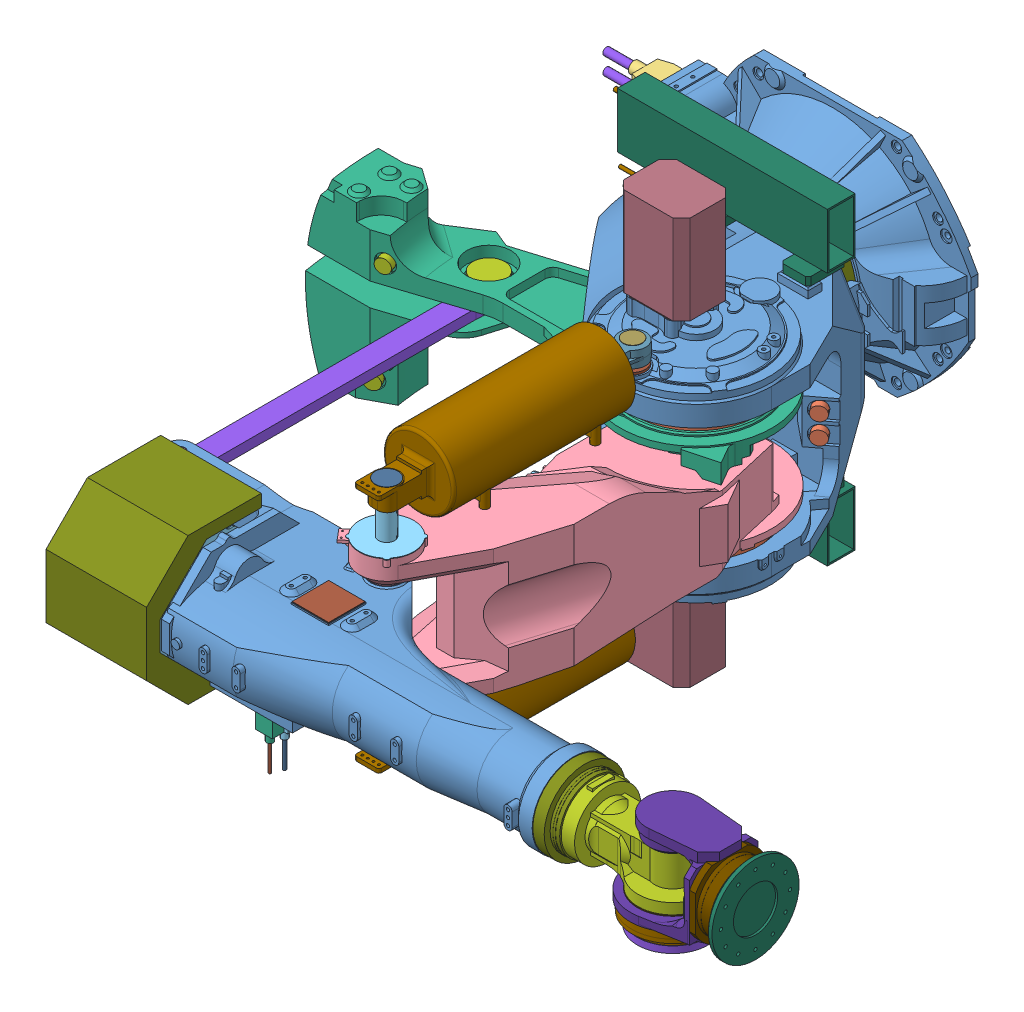
SolidWorks assembly 3D_M-900iB_700_v01, configuration По умолчанию. Lengths in mm.
Overall size (2849.18 1471 2580).
68 component instances, 53 part files, 0 mates.
Components (placement in the parent):
- S301_yellow_v1-1: S301_yellow_v1 [По умолчанию] at (0 0 940) size (1031 816 962)
- S301_black_v1-1: S301_black_v1 [По умолчанию] at (0 0 940) size (948 1369 773)
- S301_red_v1-1: S301_red_v1 [По умолчанию] at (0 0 940) size (615.67 1451.6 218.5)
- S302_yellow_v1-1: S302_yellow_v1 [По умолчанию] at (410 0 940) x (-1 0 0) z (0 0 1) size (586.92 532 1493.5)
- S302_black_v1-1: S302_black_v1 [По умолчанию] at (410 0 940) x (-1 0 0) z (0 0 1) size (238.62 719 787.58)
- S303_yellow_v1-1: S303_yellow_v1 [По умолчанию] at (410 178 940) size (1549.97 633 548)
- S303_black_v1-1: S303_black_v1 [По умолчанию] at (410 178 940) size (313.77 444 276.38)
- S304_yellow_v1-1: S304_yellow_v1 [По умолчанию] at (-340 51 2060) size (116 53 1230)
- S305_yellow_v1-1: S305_yellow_v1 [По умолчанию] at (410 394.5 1945.5) x (0 1 0) z (0 0 1) size (264 257 844.5)
- S305_yellow_v1-2: S305_yellow_v1 [По умолчанию] at (410 -394.5 1945.5) x (0 -1 0) z (0 0 1) size (264 257 844.5)
- S305_black_v1-1: S305_black_v1 [По умолчанию] at (410 435.7 2060) size (82 1.2 82)
- S305_black_v1-2: S305_black_v1 [По умолчанию] at (410 -434.5 2060) size (82 1.2 82)
- S301_black_v2-1: S301_black_v2 [По умолчанию] at (410 -345.5 1170) x (1 0 0) z (0 -1 0) size (93 93 20)
- S301_black_v2-2: S301_black_v2 [По умолчанию] at (410 345.5 1170) x (1 0 0) z (0 1 0) size (93 93 20)
- S306_black_v1-1: S306_black_v1 [По умолчанию] at (410 429.7 1170) x (1 0 0) z (0 -1 0) size (68 68 6.2)
- S306_black_v1-2: S306_black_v1 [По умолчанию] at (410 -429.7 1170) x (1 0 0) z (0 1 0) size (68 68 6.2)
- S309_black_v1-1: S309_black_v1 [По умолчанию] at (410 -135 2060) x (1 0 0) z (0 -1 0) size (109.6 109.6 10)
- S309_black_v1-2: S309_black_v1 [По умолчанию] at (410 135 2060) x (1 0 0) z (0 1 0) size (109.6 109.6 10)
- S306_yellow_v1-1: S306_yellow_v1 [По умолчанию] at (410 394.5 1170) x (1 0 0) z (0 -1 0) size (98 125 58)
- S306_yellow_v1-2: S306_yellow_v1 [По умолчанию] at (410 -394.5 1170) x (-1 0 0) z (0 1 0) size (98 125 58)
- S306_silver_v1-1: S306_silver_v1 [По умолчанию] at (410 -394.5 1922) x (1 0 0) z (0 1 0) size (40 600 40)
- S306_silver_v1-2: S306_silver_v1 [По умолчанию] at (410 394.5 1922) x (1 0 0) z (0 1 0) size (40 600 40)
- S401_black_v4-1: S401_black_v4 [По умолчанию] at (410 0 2060) size (1648.5 486.68 390.84)
- S511_yellow_v1-1: S511_yellow_v1 [По умолчанию] at (1695 0 2310) x (1 0 0) z (0 1 0) size (363 306 300.5)
- S401_red_v2-1: S401_red_v2 [По умолчанию] at (410 0 2060) size (41.3 434 304)
- S401_yellow_v1-1: S401_yellow_v1 [По умолчанию] at (410 0 2060) size (1734.5 454 556.62)
- S401_black_v1-1: S401_black_v1 [По умолчанию] at (-340 43 2060) x (1 0 0) z (0 1 0) size (50 50 8)
- S401_red_v1-1: S401_red_v1 [По умолчанию] at (-340 114.8 2060) x (1 0 0) z (0 -1 0) size (70 70 10.8)
- S401_black_v2-1: S401_black_v2 [По умолчанию] at (-340 143.7 2060) x (1 0 0) z (0 -1 0) size (40 40 28.9)
- S401_yellow_v2-1: S401_yellow_v2 [По умолчанию] at (40 0 2310) x (0 -1 0) z (0 0 1) size (500 20 388.5)
- S401_black_v3-1: S401_black_v3 [По умолчанию] at (-340 6 2060) x (1 0 0) z (0 1 0) size (116 116 37)
- S501_yellow_v2-1: S501_yellow_v2 [По умолчанию] at (1695 0 2310) x (1 0 0) z (0 -1 0) size (408 250 246)
- S501_yellow_v3-1: S501_yellow_v3 [По умолчанию] at (1695 -198 2310) x (1 0 0) z (0 1 0) size (255 255 24)
- S501_black_v2-1: S501_black_v2 [По умолчанию] at (1695 -80 2310) x (1 0 0) z (0 -1 0) size (295 295 114)
- S310_yellow_v1-1: S310_yellow_v1 [По умолчанию] at (410 0 2060) x (0 -1 0) z (0 0 1) size (210 135.83 451.78)
- S405_yellow_p_v1-1: S405_yellow_p_v1 [По умолчанию] at (395 136 2255) x (0 -1 0) z (0 0 1) size (2 132 132)
- S405_black_s_v1-1: S405_black_s_v1 [По умолчанию] at (395 135 2255) x (0 1 0) z (0 0 1) size (1 132 132)
- S406_yellow_v1-1: S406_yellow_v1 [По умолчанию] at (137 -240 2277) x (1 0 0) z (0 -1 0) size (243.36 136 6.95)
- S406_EE_v1-1: S406_EE_v1 [По умолчанию] at (137 -242 2310.5) x (0.837169 0 0.546944) z (0.546944 0 -0.837169) size (30 8.5 30)
- Part7-1: Part7 [По умолчанию] at (130 -359 465) x (1 0 0) z (0 -1 0) size (760 150 1118)
- S201_black_v2-1: S201_black_v2 [По умолчанию] at origin size (671 520 130.5)
- S406_yellow_v2-1: S406_yellow_v2 [По умолчанию] at (362 -242 2217) size (75 2 136)
- S504_black_v1-1: S504_black_v1 [По умолчанию] at (1971 0 2310) x (0 -1 0) z (-1 0 0) size (264 248 90.5)
- S201_gray_v4-1: S201_gray_v4 [По умолчанию] at origin size (1011.6 814 282)
- battery_box_v3-1: battery_box_v3 [По умолчанию] at (-509 84 358) x (0 0 -1) z (0 -1 0) size (103 11.8 103)
- rcc_RM_v1-1: rcc_RM_v1 [По умолчанию] at (-509 258 22) x (0 -1 0) z (0 0 1) size (43 142 140)
- rcc_RM_v1-2: rcc_RM_v1 [По умолчанию] at (-509 195 22) x (0 -1 0) z (0 0 1) size (43 142 140)
- rcc_RP_v1-1: rcc_RP_v1 [По умолчанию] at (-509 258 12) x (0 -1 0) z (0 0 1) size (43 134 93)
- rcc_AP_v1-1: rcc_AP_v1 [По умолчанию] at (-509 258 12) x (0 -1 0) z (0 0 1) size (29 123.07 81)
- rcc_AP_v1-2: rcc_AP_v1 [По умолчанию] at (296.5 -239.4 1844) x (0 0 1) z (-1 0 0) size (29 123.07 81)
- rcc_AS_v1-1: rcc_AS_v1 [По умолчанию] at (-509 258 11) x (0 -1 0) z (0 0 1) size (43 108 80)
- rcc_AS_v1-2: rcc_AS_v1 [По умолчанию] at (297.5 -239.4 1845.5) x (0 0 1) z (-1 0 0) size (43 108 80)
- union_v3-1: union_v3 [По умолчанию] at (-304 -239.4 2103.5) size (24 18 27.71)
- union_v3-2: union_v3 [По умолчанию] at (-254 -239.4 2103.5) size (24 18 27.71)
- union_v3-3: union_v3 [По умолчанию] at (-509 200 13) x (0 -1 0) z (0 0 1) size (24 18 27.71)
- union_v3-4: union_v3 [По умолчанию] at (-509 265 13) x (0 -1 0) z (0 0 1) size (24 18 27.71)
- cable_v2-1: cable_v2 [По умолчанию] at (-509 258 22) x (0 -1 0) z (0 0 1) size (90 100 27)
- cable_thin_v2-1: cable_thin_v2 [По умолчанию] at (-509 258 12) x (0 -1 0) z (0 0 1) size (304 126 20)
- cable_ap_v1-1: cable_ap_v1 [По умолчанию] at (-175.25 -239.4 2198.75) size (12 100 12)
- cable_as_v1-1: cable_as_v1 [По умолчанию] at (-227 -239.4 2251) size (9 100 9)
- cover_1_v1-1: cover_1_v1 [По умолчанию] at (-116.6726 -116.6726 854.5) x (-0.707107 -0.707107 0) z (0 0 1) size (271 189 316)
- cover_2_3_v1-1: cover_2_3_v1 [По умолчанию] at (325 -735.5 838) x (-1 0 0) z (0 0 1) size (240 322.5 190)
- cover_2_3_v1-2: cover_2_3_v1 [По умолчанию] at (325 735.5 838) size (240 322.5 190)
- S503_black_v1-1: S503_black_v1 [По умолчанию] at (1860.21 -33 2184.8816) x (0 1 0) z (0.829038 0 0.559193) size (66 32 2)
- S503_black_v1-2: S503_black_v1 [По умолчанию] at (1842.3158 -33 2408.5892) x (0 1 0) z (0.829038 0 -0.559193) size (66 32 2)
- flange_v2-1: flange_v2 [По умолчанию] at (1995 0 2310) x (0 1 0) z (0 0 1) size (315 30 315)
- cover4_5_6_v2-1: cover4_5_6_v2 [По умолчанию] at (61.2 0 2310) size (364 530 464.5)
- S201_black_v3_1-1: S201_black_v3_1 [По умолчанию] at (-0.7212 0.2489 -5) size (60.73 219.93 26)
